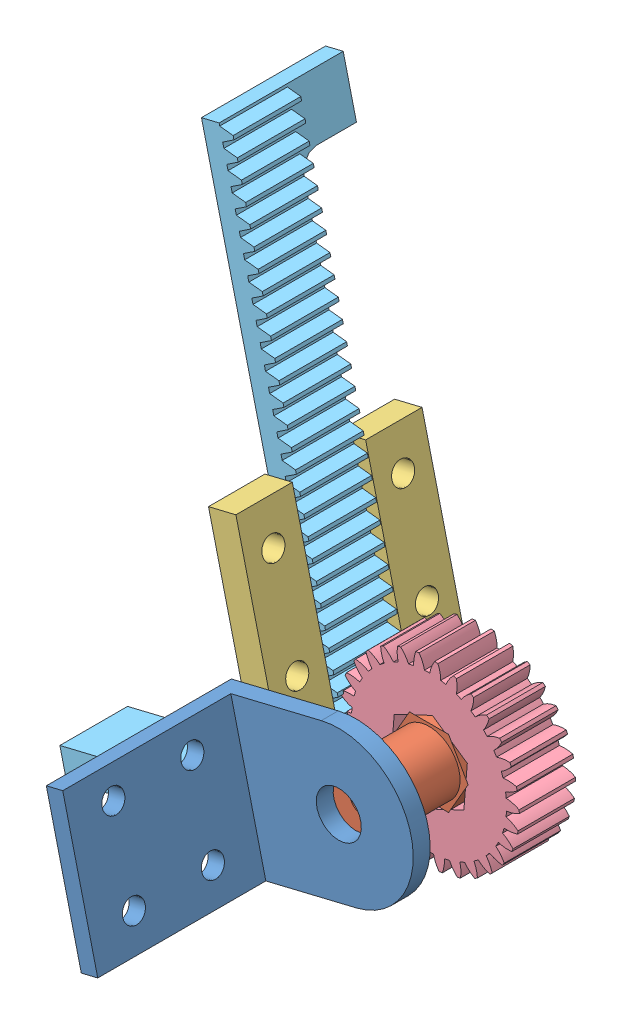
SolidWorks assembly 134, configuration Default. Lengths in mm.
Overall size (105.12 115.09 67.3).
7 component instances, 6 part files, 17 mates.
Components (placement in the parent):
- moteur-1: moteur [Default] at (-16.7446 57.6335 131.0783) (suppressed, hidden)
- support-moteur-1: support-moteur [Default] at (-35.7659 53.3297 128.0783) x (0 0 -1) z (0.234936 -0.972011 0) size (32.8 32.7 26.4)
- support-1: support [Default] at (-16.7446 57.6335 109.0783) size (13.86 12 18)
- 137-1: 137 [Default] at (-41.9144 89.4096 98.5783) x (0 0 -1) z (0.234936 -0.972011 0) size (10 5 50)
- 137-2: 137 [Default] at (-41.9144 89.4096 121.5783) x (0 0 -1) z (0.234936 -0.972011 0) size (10 5 50)
- 135_.step-1: 135_.step [Default] at (-16.7446 57.6335 105.0783) x (0 0 1) z (-0.080381 -0.996764 0) size (10 31.88 32)
- 133___.step-1: 133___.step [Default] at (-61.4664 136.1236 116.0783) x (0.234936 -0.972011 0) z (0 0 1) size (105 55.47 22)
Mates (geometry in assembly coordinates):
- Concentric1: concentric aligned: cylinder of moteur-1 through (-16.7446 57.6335 119.0783) axis (0 0 1) radius 1.75; cylinder of support moteur-1 through (-16.7446 57.6335 119.0783) axis (0 0 1) radius 4
- Coincident1: coincident anti-aligned: plane of moteur-1 through (-16.7446 57.6335 131.0783) normal (0 0 -1); plane of support moteur-1 through (-3.9811 61.0121 131.0783) normal (0 0 1)
- Concentric2: concentric anti-aligned: cylinder of moteur-1 through (-16.7446 57.6335 119.0783) axis (0 0 1) radius 1.75; cylinder of support-1 through (-16.7446 57.6335 115.0783) axis (0 0 -1) radius 2
- Distance1: distance = 1 mm anti-aligned: plane of support moteur-1 through (-3.9811 61.0121 128.0783) normal (0 0 -1); plane of support-1 through (-16.7446 57.6335 127.0783) normal (0 0 1)
- Parallel4: parallel aligned: plane of support moteur-1 through (-35.7659 53.3297 128.0783) normal (-0.972011 -0.234936 0); plane of 137-1 through (-32.5976 40.2217 103.5783) normal (-0.972011 -0.234936 0)
- Coincident13: coincident aligned: plane of support moteur-1 through (-35.7659 53.3297 128.0783) normal (-0.972011 -0.234936 0); plane of 137-1 through (-32.5976 40.2217 103.5783) normal (-0.972011 -0.234936 0)
- Coincident14: coincident aligned: plane of support moteur-1 through (-0.8129 47.9041 128.0783) normal (0.234936 -0.972011 0); plane of 137-1 through (-30.1676 40.809 98.5783) normal (0.234936 -0.972011 0)
- Coincident15: coincident aligned: plane of 137-1 through (-30.1676 40.809 98.5783) normal (0.234936 -0.972011 0); plane of 137-2 through (-30.1676 40.809 121.5783) normal (0.234936 -0.972011 0)
- Coincident16: coincident aligned: plane of 137-1 through (-32.5976 40.2217 103.5783) normal (-0.972011 -0.234936 0); plane of 137-2 through (-32.5976 40.2217 126.5783) normal (-0.972011 -0.234936 0)
- Concentric3: concentric aligned: cylinder of support-1 through (-16.7446 57.6335 115.0783) axis (0 0 -1) radius 2; cylinder of 135_.step-1 through (-16.7446 57.6335 111.0783) axis (0 0 -1) radius 2.25
- Coincident17: coincident anti-aligned: plane of support-1 through (-16.7446 57.6335 109.0783) normal (0 0 -1); plane of 135_.step-1 through (-16.7446 57.6335 109.0783) normal (0 0 1)
- Coincident22: coincident aligned: plane of 137-1 through (-30.1676 40.809 98.5783) normal (0.234936 -0.972011 0); plane of 137-2 through (-30.1676 40.809 121.5783) normal (0.234936 -0.972011 0)
- Width1: width aligned: plane of 137-2 through (-27.7376 41.3964 116.5783) normal (0 0 -1); plane of 137-1 through (-27.7376 41.3964 103.5783) normal (0 0 1); plane of 133___.step-1 through (-50.7743 138.7079 104.0783) normal (0 0 -1); plane of 133___.step-1 through (-50.7743 138.7079 116.0783) normal (0 0 1)
- Coincident23: coincident aligned: plane of 137-1 through (-32.5976 40.2217 103.5783) normal (-0.972011 -0.234936 0); plane of 133___.step-1 through (-62.1995 162.6951 116.0783) normal (-0.972011 -0.234936 0)
- Coincident24: coincident anti-aligned: plane of 137-1 through (-30.1676 40.809 98.5783) normal (0.234936 -0.972011 0); plane of 133___.step-1 through (-81.1982 28.4749 116.0783) normal (-0.234936 0.972011 0)
- Width2: width anti-aligned: plane of 137-2 through (-27.7376 41.3964 116.5783) normal (0 0 -1); plane of 137-1 through (-27.7376 41.3964 103.5783) normal (0 0 1); plane of 135_.step-1 through (-16.7446 57.6335 115.0783) normal (0 0 1); plane of 135_.step-1 through (-16.7446 57.6335 105.0783) normal (0 0 -1)
- Distance2: distance = 0.5 mm anti-aligned: plane of 137-2 through (-27.7376 41.3964 116.5783) normal (0 0 -1); plane of 133___.step-1 through (-50.7743 138.7079 116.0783) normal (0 0 1)
